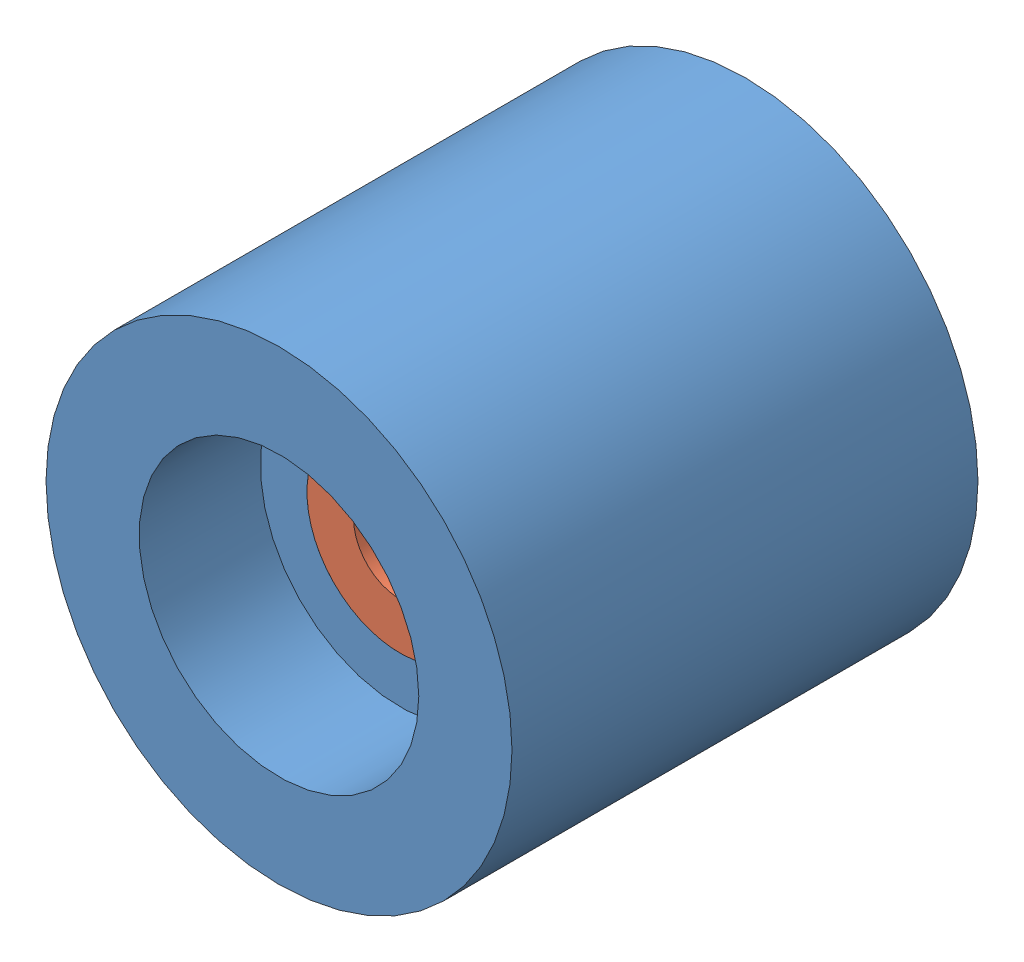
SolidWorks assembly Oil Bearing, configuration Predeterminado. Lengths in mm.
Overall size (5 5 5).
4 component instances, 3 part files, 10 mates.
Components (placement in the parent):
- Bearing-1: Bearing [Predeterminado] at origin size (5 5 5)
- Bearing gasket-1: Bearing gasket [Predeterminado] at (0 0 -1.3) size (2 2 0.5)
- Oil-1: Oil [Predeterminado] at (0 0 -4.5) size (4 4 2.7)
- Bearing gasket-2: Bearing gasket [Predeterminado] at (0 0 -4.5) size (2 2 0.5)
Mates (geometry in assembly coordinates):
- Coincidente1: coincident aligned: plane of Bearing-1 through (0 0 0) normal (0 0 1)
- Coincidente2: coincident aligned: plane of Bearing-1 through (0 0 0) normal (0 1 0)
- Coincidente3: coincident aligned: plane of Bearing-1 through (0 0 0) normal (1 0 0)
- Coincidente4: coincident aligned: plane of Bearing gasket-1 through (0 0 -1.3) normal (0 1 0)
- Concéntrica1: concentric aligned: cylinder of Bearing-1 through (0 0 0) axis (0 0 1) radius 1; cylinder of Bearing gasket-1 through (0 0 -1.3) axis (0 0 1) radius 1
- Coincidente5: coincident aligned: plane of Bearing-1 through (-1.5 0 -1.3) normal (0 0 1); plane of Bearing gasket-1 through (0.5 0 -1.3) normal (0 0 1)
- Concéntrica2: concentric anti-aligned: cylinder of Bearing-1 through (0 0 0) axis (0 0 1) radius 2; cylinder of Oil-1 through (0 0 -1.8) axis (0 0 -1) radius 2
- Coincidente6: coincident anti-aligned: plane of Bearing-1 through (-2 0 -1.8) normal (0 0 -1); plane of Oil-1 through (0 0 -1.8) normal (0 0 1)
- Concéntrica3: concentric aligned: cylinder of Bearing-1 through (0 0 0) axis (0 0 1) radius 1; cylinder of Bearing gasket-2 through (0 0 -4.5) axis (0 0 1) radius 1
- Coincidente7: coincident aligned: plane of Bearing-1 through (-2.5 0 -5) normal (0 0 -1); plane of Bearing gasket-2 through (0.5 0 -5) normal (0 0 -1)
